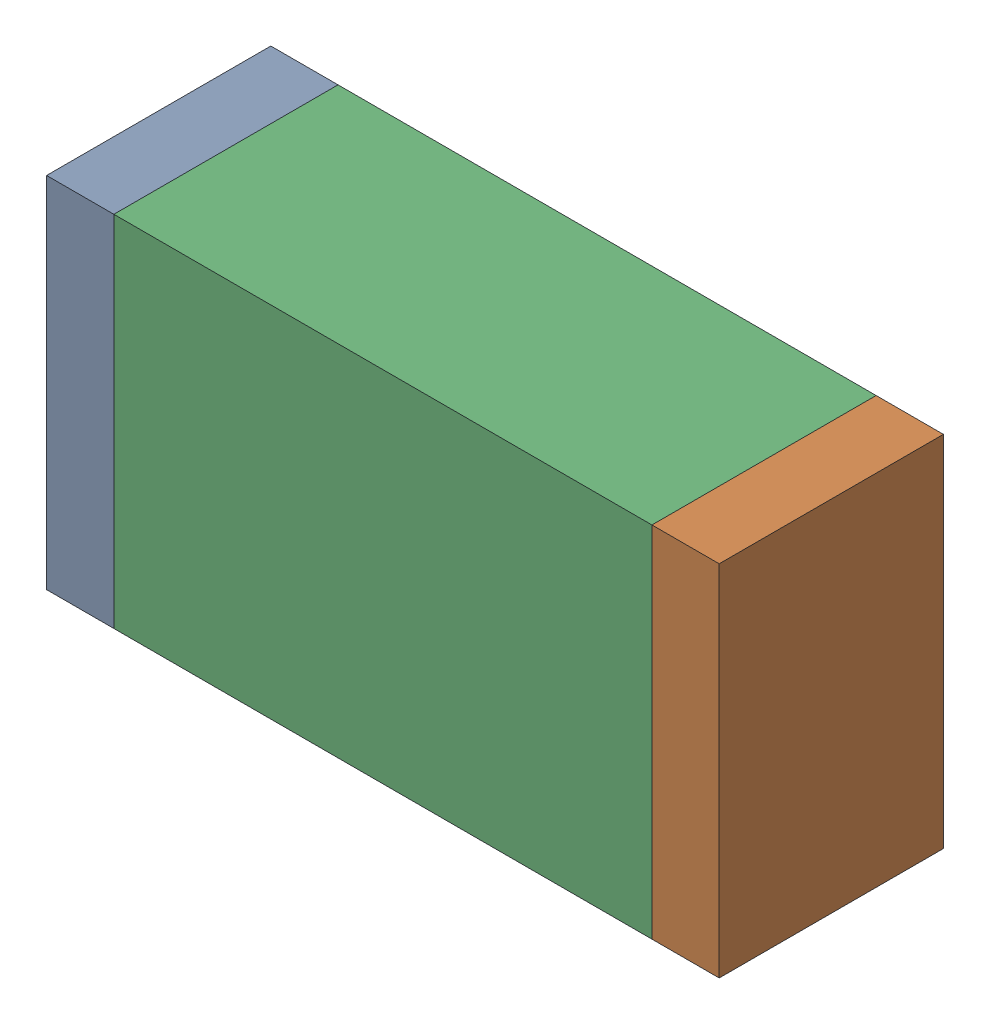
SolidWorks assembly R68, configuration Default. Lengths in mm.
Overall size (1.5 0.8 0.5).
6 component instances, 2 part files, 0 mates.
Components (placement in the parent):
- 836752496-1: 836752496 [Default] at (117.175 74.3 0) size (0.15 0.8 0.5)
  - Extruded_2-1: Extruded_2 [Default] at origin size (0.15 0.8 0.5)
- 836752496-2: 836752496 [Default] at (118.525 74.3 0) size (0.15 0.8 0.5)
  - Extruded_2-1: Extruded_2 [Default] at origin size (0.15 0.8 0.5)
- 836752368-1: 836752368 [Default] at (117.85 74.3 0) size (1.2 0.8 0.5)
  - Extruded-1: Extruded [Default] at origin size (1.2 0.8 0.5)
